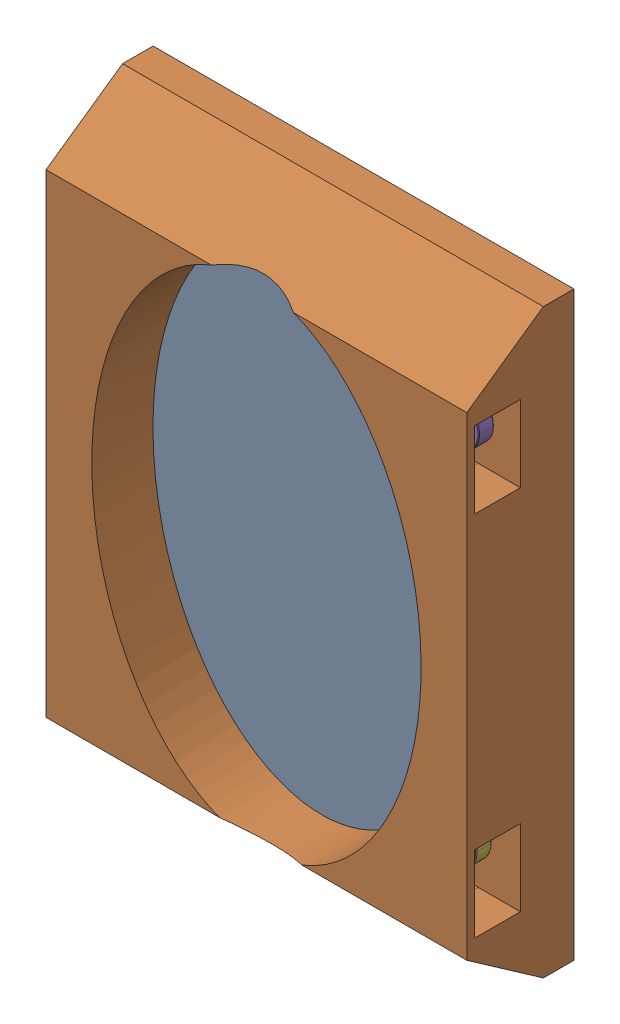
SolidWorks assembly assembly_holder_colorCombiner_mirror_openSIM_V2.0, configuration Default. Lengths in mm.
Overall size (27.72 38 7.3).
6 component instances, 3 part files, 3 mates.
Components (placement in the parent):
- mirror_openSIM_V2.0-1: mirror_openSIM_V2.0 [Default] at (0.2217 0.7846 26.1207) size (25 35.6 3)
- holder_colorCombiner_mirror_openSIM_V2.0-1: holder_colorCombiner_mirror_openSIM_V2.0 [Default] at (12.9717 18.3846 26.1207) x (0 -1 0) z (1 0 0) size (38 7.3 27.5)
- HXN3_1_openSIM_V2.0-1: HXN3_1_openSIM_V2.0 [Default] at (0.5043 6.2183 31.0816) x (0 0 -1) z (1 0 0) size (1 3 3)
- HXN3_1_openSIM_V2.0-2: HXN3_1_openSIM_V2.0 [Default] at (2.5307 29.9308 30.6222) x (0 0 -1) z (1 0 0) size (1 3 3)
- HXN3_1_openSIM_V2.0-3: HXN3_1_openSIM_V2.0 [Default] at (23.5053 30.5229 30.6228) x (0 0 -1) z (1 0 0) size (1 3 3)
- HXN3_1_openSIM_V2.0-4: HXN3_1_openSIM_V2.0 [Default] at (23.333 6.8123 30.6079) x (0 0 -1) z (1 0 0) size (1 3 3)
Mates (geometry in assembly coordinates):
- Coincident1: coincident anti-aligned: plane of mirror_20200728-1 through (0.2217 36.3846 29.1207) normal (0 1 0); plane of holder_colorCombiner_mirror_20200806-1 through (0.2217 36.3846 29.1207) normal (0 -1 0)
- Coincident2: coincident anti-aligned: line of mirror_20200728-1 through (25.2217 36.3846 26.1207) axis (-1 0 0); line of holder_colorCombiner_mirror_20200806-1 through (0.2217 36.3846 26.1207) axis (1 0 0)
- Coincident3: coincident anti-aligned: plane of mirror_20200728-1 through (0.2217 0.7846 29.1207) normal (-1 0 0); plane of holder_colorCombiner_mirror_20200806-1 through (0.2217 36.3846 29.1207) normal (1 0 0)
